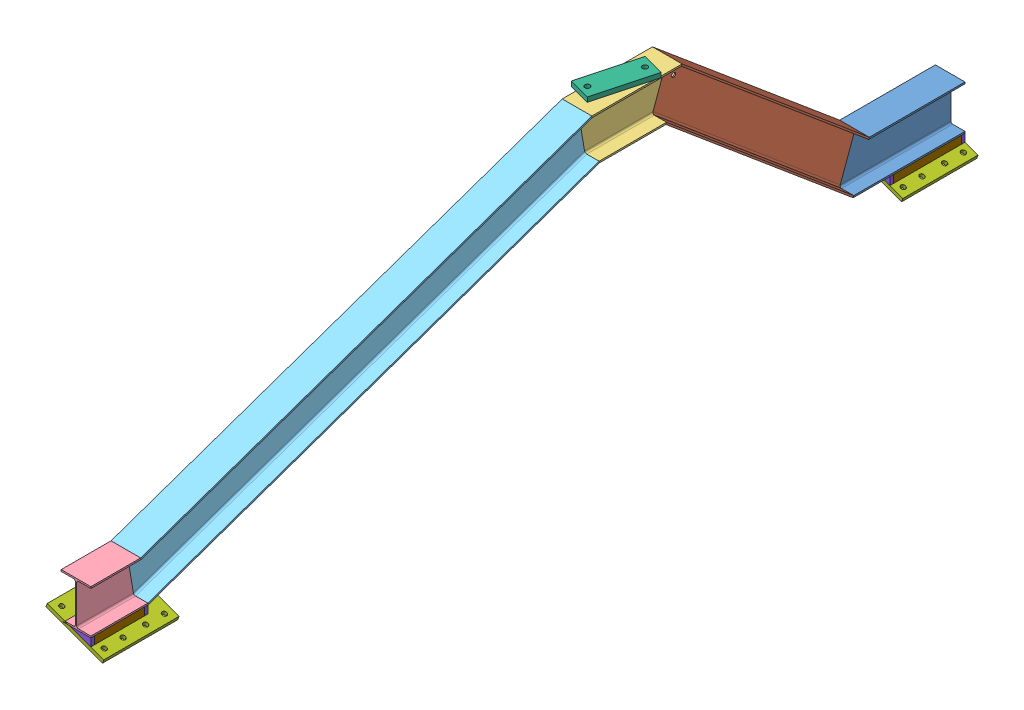
SolidWorks assembly _2014-10-29 WELDMENT, PORT BOOM BASE, configuration Default. Lengths in mm.
Overall size (195.29 750.52 2952.75).
14 component instances, 9 part files, 32 mates.
Components (placement in the parent):
- BEAM 1, BASE 2-3: BEAM 1, BASE 2 [Default] at origin size (100.08 149.86 377.86)
- BEAM 2, BASE 2-1: BEAM 2, BASE 2 [Default] at (0 17.5303 371.475) x (1 0 0) z (0 0.642788 0.766044) size (100.08 149.86 880.04)
- BEAM 3, BASE 2-2: BEAM 3, BASE 2 [Default] at (0 530.6212 955.6806) size (100.08 149.86 304.8)
- BEAM 5, BASE 2-1: BEAM 5, BASE 2 [Default] at (0 0 2784.475) size (100.08 149.86 193.62)
- BEAM 4, BASE 2-1: BEAM 4, BASE 2 [Default] at (0 534.7878 1235.8422) x (1 0 0) z (0 -0.328817 0.944394) size (100.08 149.86 1639.07)
- PLATE, PILLOW BLOCK MOUNTING, BASE 1,2-1: PLATE, PILLOW BLOCK MOUNTING, BASE 1,2 [Default] at (-8.0928 621.4262 1120.1576) x (0 -1 0) z (-0.258819 0 0.965926) size (15.88 76.2 203.2)
- PLATE, PLATFORM MOUNTING, BASE 1,2-1: PLATE, PLATFORM MOUNTING, BASE 1,2 [Default] at (-5.967 -94.3482 127) x (0.34202 0.939693 0) z (0 0 1) size (12.7 203.2 254)
- FILLER PLATE 3-1: FILLER PLATE 3 [Default] at (-22.987 -74.93 0) size (73.03 26.58 12.7)
- FILLER PLATE 4-1: FILLER PLATE 4 [LENGTH 2] at (37.338 -74.93 12.7) x (0 0 1) z (-1 0 0) size (228.6 26.58 12.7)
- FILLER PLATE 3-2: FILLER PLATE 3 [Default] at (-22.987 -74.93 241.3) size (73.03 26.58 12.7)
- PLATE, PLATFORM MOUNTING, BASE 1,2-3: PLATE, PLATFORM MOUNTING, BASE 1,2 [Default] at (-5.967 -94.3482 2825.75) x (0.34202 0.939693 0) z (0 0 1) size (12.7 203.2 254)
- FILLER PLATE 3-9: FILLER PLATE 3 [Default] at (-22.987 -74.93 2940.05) size (73.03 26.58 12.7)
- FILLER PLATE 4-2: FILLER PLATE 4 [Default] at (37.338 -74.93 2771.8309) x (0 0 1) z (-1 0 0) size (168.22 26.58 12.7)
- FILLER PLATE 3-10: FILLER PLATE 3 [Default] at (-22.987 -74.93 2759.1309) size (73.03 26.58 12.7)
Mates (geometry in assembly coordinates):
- Coincident1: coincident aligned: line of BEAM 1, BASE 2-3 through (50.038 74.93 323.3109) axis (-1 0 0); line of BEAM 2, BASE 2-1 through (50.038 74.93 323.3109) axis (-1 0 0)
- Coincident2: coincident aligned: plane of BEAM 1, BASE 2-3 through (0 0 0) normal (1 0 0); plane of BEAM 2, BASE 2-1
- Coincident3: coincident aligned: line of BEAM 1, BASE 2-3 through (-50.038 -74.93 377.8555) axis (1 0 0); line of BEAM 2, BASE 2-1 through (-50.038 -74.93 377.8555) axis (1 0 0)
- Coincident4: coincident aligned: plane of BEAM 1, BASE 2-3 through (0 0 0) normal (0 1 0); plane of assembly through (0 0 0) normal (0 1 0)
- Coincident5: coincident aligned: plane of BEAM 1, BASE 2-3 through (0 0 0) normal (1 0 0); plane of assembly through (0 0 0) normal (1 0 0)
- Coincident6: coincident aligned: plane of BEAM 1, BASE 2-3 through (0 0 0) normal (0 0 1); plane of assembly through (0 0 0) normal (0 0 1)
- Coincident7: coincident aligned: line of BEAM 2, BASE 2-1 through (50.038 605.5512 955.6806) axis (-1 0 0); line of BEAM 3, BASE 2-2 through (50.038 605.5512 955.6806) axis (-1 0 0)
- Coincident8: coincident aligned: plane of BEAM 3, BASE 2-2 through (0 530.6212 955.6806) normal (1 0 0); plane of assembly through (0 0 0) normal (1 0 0)
- Parallel1: parallel aligned: plane of BEAM 3, BASE 2-2 through (0 530.6212 955.6806) normal (0 1 0); plane of assembly through (0 0 0) normal (0 1 0)
- Coincident10: coincident aligned: plane of BEAM 5, BASE 2-1 through (0 0 2784.475) normal (1 0 0); plane of assembly through (0 0 0) normal (1 0 0)
- Coincident11: coincident aligned: plane of BEAM 5, BASE 2-1 through (0 0 2784.475) normal (0 1 0); plane of assembly through (0 0 0) normal (0 1 0)
- Distance1: distance = 2952.75 mm anti-aligned: plane of BEAM 5, BASE 2-1 through (8.509 63.119 2952.75) normal (0 0 1); plane of BEAM 1, BASE 2-3 through (8.509 63.119 0) normal (0 0 -1)
- Coincident13: coincident aligned: line of BEAM 5, BASE 2-1 through (50.038 74.93 2784.475) axis (-1 0 0); line of BEAM 4, BASE 2-1 through (50.038 74.93 2784.475) axis (-1 0 0)
- Coincident14: coincident aligned: plane of BEAM 4, BASE 2-1; plane of assembly through (0 0 0) normal (1 0 0)
- Coincident15: coincident: line of BEAM 3, BASE 2-2 through (50.038 605.5512 1260.4806) axis (-1 0 0); plane of BEAM 4, BASE 2-1 through (-50.038 74.93 2784.475) normal (0 0.944394 0.328817)
- Coincident16: coincident anti-aligned: plane of BEAM 3, BASE 2-2 through (-50.038 605.5512 1260.4806) normal (0 1 0); plane of PLATE, PILLOW BLOCK MOUNTING, BASE 1,2-1 through (-8.0928 605.5512 1120.1576) normal (0 -1 0)
- Coincident21: coincident anti-aligned: plane of PLATE, PLATFORM MOUNTING, BASE 1,2-1 through (-97.0962 -47.6648 0) normal (0 0 -1); plane of assembly through (0 0 0) normal (0 0 1)
- Coincident22: coincident: line of PLATE, PLATFORM MOUNTING, BASE 1,2-1 through (0 -96.52 266.7) axis (0 0 -1); plane of assembly
- Distance5: distance = 171.45 mm: line of PLATE, PLATFORM MOUNTING, BASE 1,2-1 through (0 -96.52 266.7) axis (0 0 -1); plane of BEAM 1, BASE 2-3 through (-50.038 74.93 377.8555) normal (0 1 0)
- Angle2: planar angle = 0.349066 rad aligned: plane of assembly through (0 0 0) normal (0 1 0); plane of PLATE, PLATFORM MOUNTING, BASE 1,2-1
- Concentric1: concentric anti-aligned: cylinder of BEAM 3, BASE 2-2 through (12.451 580.1512 1043.4873) axis (0 1 0) radius 8.7312; cylinder of PLATE, PILLOW BLOCK MOUNTING, BASE 1,2-1 through (12.451 605.5512 1043.4873) axis (0 -1 0) radius 8.7312
- Concentric2: concentric anti-aligned: cylinder of BEAM 3, BASE 2-2 through (-28.6365 580.1512 1196.828) axis (0 1 0) radius 8.7312; cylinder of PLATE, PILLOW BLOCK MOUNTING, BASE 1,2-1 through (-28.6365 605.5512 1196.828) axis (0 -1 0) radius 8.7312
- Coincident27: coincident anti-aligned: plane of BEAM 5, BASE 2-1 through (50.038 -74.93 2952.75) normal (0 -1 0); plane of FILLER PLATE 4-1 through (37.338 -74.93 241.3) normal (0 1 0)
- Coincident30: coincident aligned: plane of BEAM 1, BASE 2-3 through (8.509 63.119 0) normal (0 0 -1); plane of FILLER PLATE 3-1 through (-22.987 -74.93 0) normal (0 0 -1)
- Coincident31: coincident anti-aligned: plane of BEAM 1, BASE 2-3 through (50.038 -74.93 377.8555) normal (0 -1 0); plane of FILLER PLATE 3-1 through (-22.987 -74.93 12.7) normal (0 1 0)
- Coincident32: coincident aligned: plane of BEAM 1, BASE 2-3 through (50.038 -69.469 377.8555) normal (1 0 0); plane of FILLER PLATE 3-1 through (50.038 -74.93 12.7) normal (1 0 0)
- Coincident33: coincident anti-aligned: plane of BEAM 1, BASE 2-3 through (50.038 -74.93 377.8555) normal (0 -1 0); plane of FILLER PLATE 4-1 through (37.338 -74.93 241.3) normal (0 1 0)
- Coincident34: coincident aligned: plane of FILLER PLATE 3-1 through (50.038 -74.93 12.7) normal (1 0 0); plane of FILLER PLATE 4-1 through (50.038 -74.93 241.3) normal (1 0 0)
- Coincident35: coincident anti-aligned: plane of FILLER PLATE 4-1 through (37.338 -74.93 241.3) normal (0 0 1); plane of FILLER PLATE 3-2 through (-22.987 -74.93 241.3) normal (0 0 -1)
- Coincident36: coincident anti-aligned: plane of BEAM 5, BASE 2-1 through (50.038 -74.93 2952.75) normal (0 -1 0); plane of FILLER PLATE 4-2 through (37.338 -74.93 2940.05) normal (0 1 0)
- Coincident37: coincident anti-aligned: plane of FILLER PLATE 3-9 through (-22.987 -74.93 2940.05) normal (0 0 -1); plane of FILLER PLATE 4-2 through (37.338 -74.93 2940.05) normal (0 0 1)
- Coincident38: coincident aligned: plane of BEAM 5, BASE 2-1 through (50.038 -69.469 2952.75) normal (1 0 0); plane of FILLER PLATE 4-2 through (50.038 -74.93 2940.05) normal (1 0 0)
